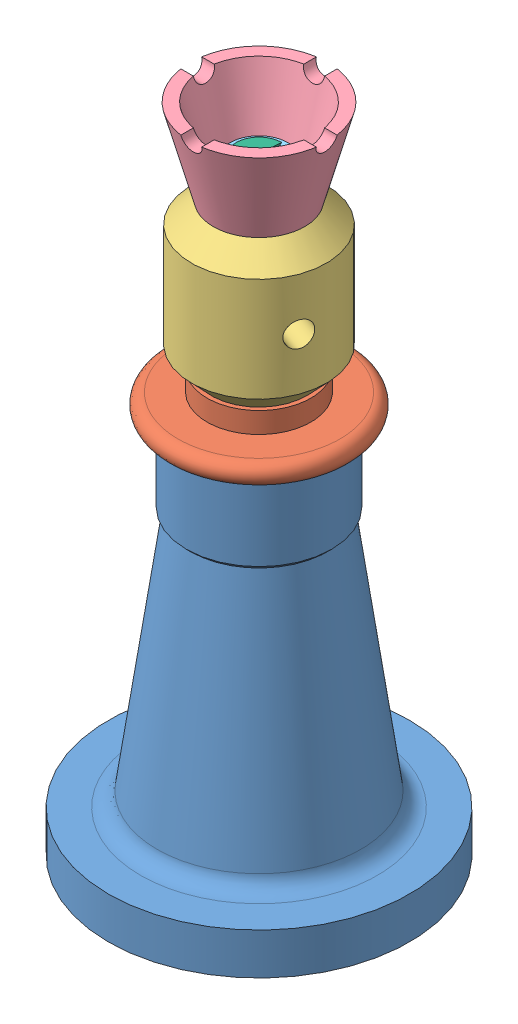
SolidWorks assembly Assem2, configuration Default. Lengths in mm.
Overall size (145 314.3 145).
6 component instances, 6 part files, 10 mates.
Components (placement in the parent):
- Part1-1: Part1 [Default] at origin size (145 183 145)
- Part3-1: Part3 [Default] at (0 170.0238 0) size (88 45 88)
- Part4-2: Part4 [Default] at (0 200.0455 0) x (0.940144 0 0.340779) z (-0.340779 0 0.940144) size (65 244 65)
- Part2-2: Part2 [Default] at (0 297.0359 0) size (65.84 41.3 65.84)
- Part6-1: Part6 [Default] at (0 281.1034 0) size (34 6 34)
- Part5-2: Part5 [Default] at (3.2892 265.8214 0.2969) x (0.995951 0 0.089894) z (-0.089894 0 0.995951) size (22 28.59 21.91)
Mates (geometry in assembly coordinates):
- Concentric2: concentric aligned: cylinder of Part1-1 through (0 94.0385 0) axis (0 1 0) radius 25; cylinder of Part3-1 through (0 208.4762 0) axis (0 1 0) radius 18.5
- Coincident2: coincident anti-aligned: plane of Part1-1 through (25 183 0) normal (0 1 0); plane of Part3-1 through (39 183 0) normal (0 -1 0)
- Concentric4: concentric aligned: cylinder of Part3-1 through (0 208.4762 0) axis (0 1 0) radius 18.5; cylinder of Part4-2 through (0 323.4545 0) axis (0 1 0) radius 20
- Coincident4: coincident anti-aligned: plane of Part3-1 through (18.5 203 0) normal (0 1 0); plane of Part4-2 through (21.6009 203 7.8298) normal (0 -1 0)
- Coincident6: coincident anti-aligned: plane of Part4-2 through (10.3416 273 3.7486) normal (0 1 0); plane of Part2-2 through (22 273 0) normal (0 -1 0)
- Concentric5: concentric aligned: cylinder of Part4-2 through (0 323.4545 0) axis (0 1 0) radius 11; cylinder of Part2-2 through (0 319.1878 0) axis (0 1 0) radius 11
- Coincident7: coincident anti-aligned: plane of Part2-2 through (11 284 0) normal (0 1 0); plane of Part6-1 through (5 284 0) normal (0 -1 0)
- Concentric6: concentric anti-aligned: circle of Part4-2; circle of Part6-1
- Concentric11: concentric aligned: cone of Part6-1 through (0 290 0) axis (0 -1 0); cone of Part5-2 through (0 374.9429 0) axis (0 -1 0)
- Coincident8: coincident aligned: plane of Part4-2 through (0 263 0) normal (0 1 0); circle of Part5-2
